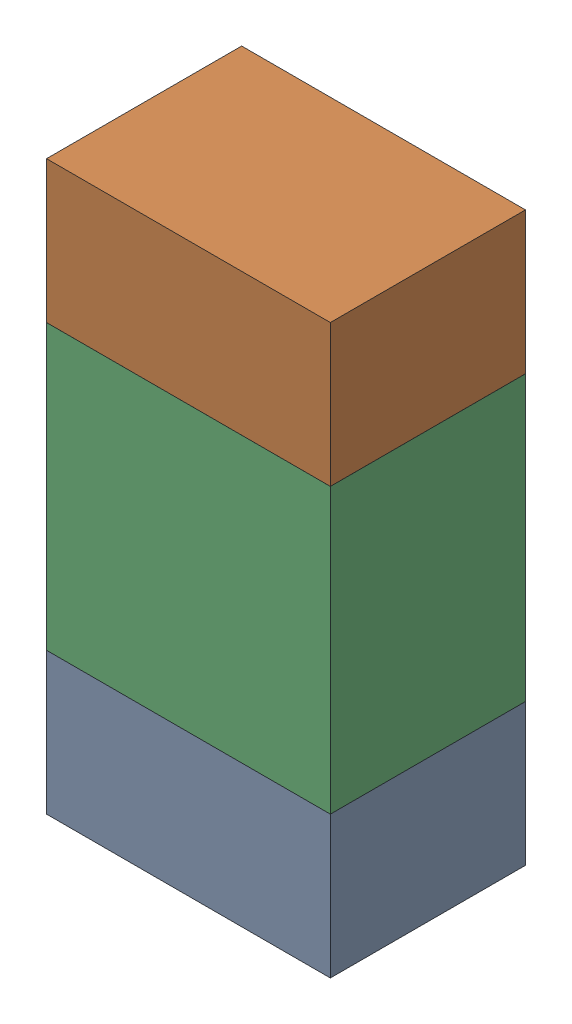
SolidWorks assembly R38, configuration ﾃﾞﾌｫﾙﾄ. Lengths in mm.
Overall size (0.8 1.6 0.55).
6 component instances, 2 part files, 0 mates.
Components (placement in the parent):
- 689261784-1: 689261784 [ﾃﾞﾌｫﾙﾄ] at (18.4999 69.1501 0) size (0.8 0.4 0.55)
  - Extruded_34-1: Extruded_34 [ﾃﾞﾌｫﾙﾄ] at origin size (0.8 0.4 0.55)
- 689261784-2: 689261784 [ﾃﾞﾌｫﾙﾄ] at (18.4999 70.3501 0) size (0.8 0.4 0.55)
  - Extruded_34-1: Extruded_34 [ﾃﾞﾌｫﾙﾄ] at origin size (0.8 0.4 0.55)
- 689261648-1: 689261648 [ﾃﾞﾌｫﾙﾄ] at (18.4999 69.75 0) size (0.8 0.8 0.55)
  - Extruded_33-1: Extruded_33 [ﾃﾞﾌｫﾙﾄ] at origin size (0.8 0.8 0.55)
